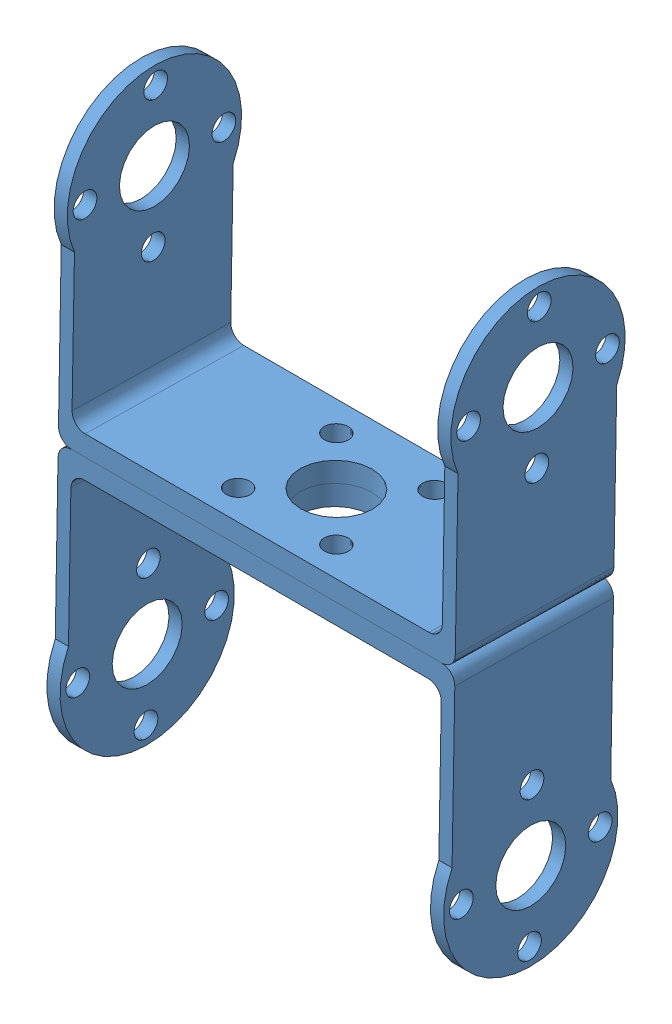
SolidWorks assembly box3, configuration Predeterminado. Lengths in mm.
Overall size (60 88.89 27.92).
2 component instances, 1 part files, 3 mates.
Components (placement in the parent):
- u_bracket-1: u_bracket [Predeterminado] at (-8.8521 -59.797 10.5608) x (1 0 0) z (0 0.017646 0.999844) size (60 44.22 26.36)
- u_bracket-2: u_bracket [Predeterminado] at (-8.8521 -61.7967 10.5961) x (-1 0 0) z (0 0.017646 0.999844) size (60 44.22 26.36)
Mates (geometry in assembly coordinates):
- Coincidente1: coincident anti-aligned: plane of u_bracket-1 through (-8.8521 -60.7968 10.5785) normal (0 -0.999844 0.017646); plane of u_bracket-2 through (-8.8521 -60.7968 10.5785) normal (0 0.999844 -0.017646)
- Concéntrica1: concentric anti-aligned: circle of u_bracket-1; circle of u_bracket-2
- Coincidente3: coincident aligned: plane of u_bracket-1 through (-38.8521 -57.5855 22.5237) normal (0 0.017646 0.999844); plane of u_bracket-2 through (21.1479 -63.5846 22.6296) normal (0 0.017646 0.999844)
